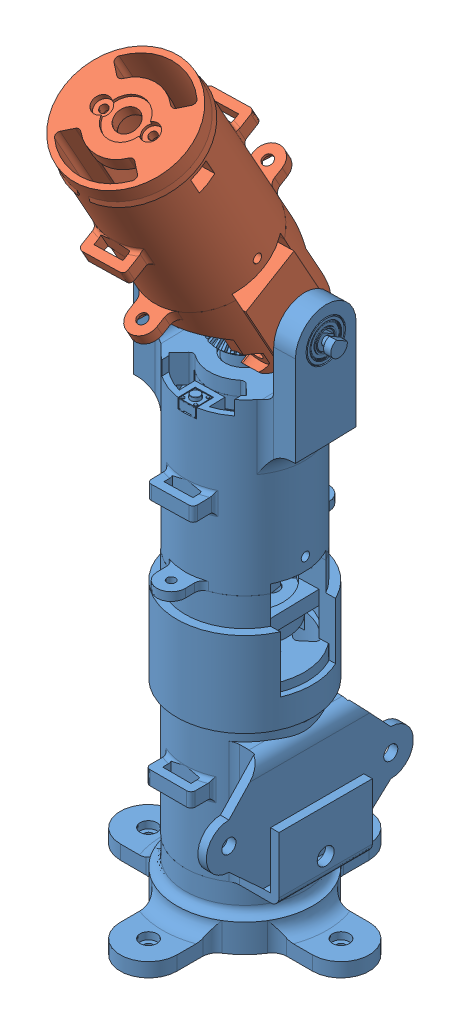
SolidWorks assembly Manipulador, configuration Default. Lengths in mm.
Overall size (88 277.01 118.2).
2 component instances, 2 part files, 2 mates.
Components (placement in the parent):
- Manipulador_Base-1: Manipulador_Base [Default] at (-7.3463 26.3558 155.1972) x (1 0 0) z (0 1 0) size (88 88 195.7)
- Manipulador_Grado-1: Manipulador_Grado [Default] at (-5.1711 -28.2679 269.213) x (0.999767 0.019118 -0.010032) z (-0.019118 0.567971 -0.822826) size (43.7 99.06 62.09)
Mates (geometry in assembly coordinates):
- Concentric1: concentric aligned: cylinder of Manipulador_Base-1 through (108.566 163.991 164.8851) axis (-0.99973 0 0.023228) radius 3; cylinder of Manipulador_Grado-1 through (68.4298 163.991 165.8177) axis (-0.99973 0 0.023228) radius 3.175
- Coincident1: coincident anti-aligned: plane of Manipulador_Base-1 through (55.4915 145.991 166.1183) normal (0.99973 0 -0.023228); plane of Manipulador_Grado-1 through (55.2332 161.0527 155.003) normal (-0.99973 0 0.023228)
